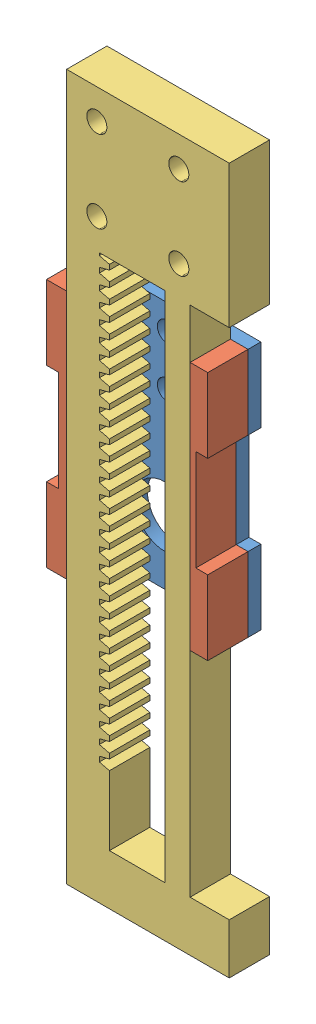
SolidWorks assembly Assem1, configuration Default. Lengths in mm.
Overall size (36.26 140 10.54).
4 component instances, 3 part files, 9 mates.
Components (placement in the parent):
- top-bottom plate-1: top-bottom plate [Default] at (16.2461 21.1572 21.9026) size (32 49.5 2.54)
- side support-4: side support [Default] at (2.2461 21.1572 24.4426) x (0 -1 0) z (0 0 1) size (49.5 4 8)
- side support-5: side support [Default] at (30.2461 21.1572 24.4426) x (0 1 0) z (0 0 1) size (49.5 4 8)
- RACK-1: RACK [Default] at (18.3778 -55.9793 24.4426) x (0 -1 0) z (0 0 1) size (140 32.26 8)
Mates (geometry in assembly coordinates):
- Coincident13: coincident aligned: line of top-bottom plate-1 through (0.2461 11.1572 24.4426) axis (0 -1 0); line of side support-4 through (0.2461 11.1572 24.4426) axis (0 -1 0)
- Coincident14: coincident aligned: line of top-bottom plate-1 through (0.2461 45.9072 24.4426) axis (0 -1 0); line of side support-4 through (0.2461 45.9072 24.4426) axis (0 -1 0)
- Coincident15: coincident aligned: plane of top-bottom plate-1 through (0.2461 31.1572 24.4426) normal (0 -1 0); plane of side support-4 through (0.2461 31.1572 32.4426) normal (0 -1 0)
- Coincident16: coincident anti-aligned: plane of top-bottom plate-1 through (16.2461 21.1572 24.4426) normal (0 0 1); plane of side support-4 through (2.2461 21.1572 24.4426) normal (0 0 -1)
- Coincident17: coincident aligned: line of top-bottom plate-1 through (32.2461 31.1572 24.4426) axis (0 1 0); line of side support-5 through (32.2461 31.1572 24.4426) axis (0 1 0)
- Coincident18: coincident aligned: plane of top-bottom plate-1 through (32.2461 31.1572 24.4426) normal (0 -1 0); plane of side support-5 through (32.2461 31.1572 32.4426) normal (0 -1 0)
- Coincident19: coincident anti-aligned: plane of top-bottom plate-1 through (16.2461 21.1572 24.4426) normal (0 0 1); plane of side support-5 through (30.2461 21.1572 24.4426) normal (0 0 -1)
- Coincident20: coincident anti-aligned: plane of side support-4 through (4.2461 45.9072 32.4426) normal (1 0 0); plane of RACK-1 through (4.2461 -46.0107 32.4426) normal (-1 0 0)
- Coincident21: coincident anti-aligned: plane of top-bottom plate-1 through (16.2461 21.1572 24.4426) normal (0 0 1); plane of RACK-1 through (18.3778 -55.9793 24.4426) normal (0 0 -1)
